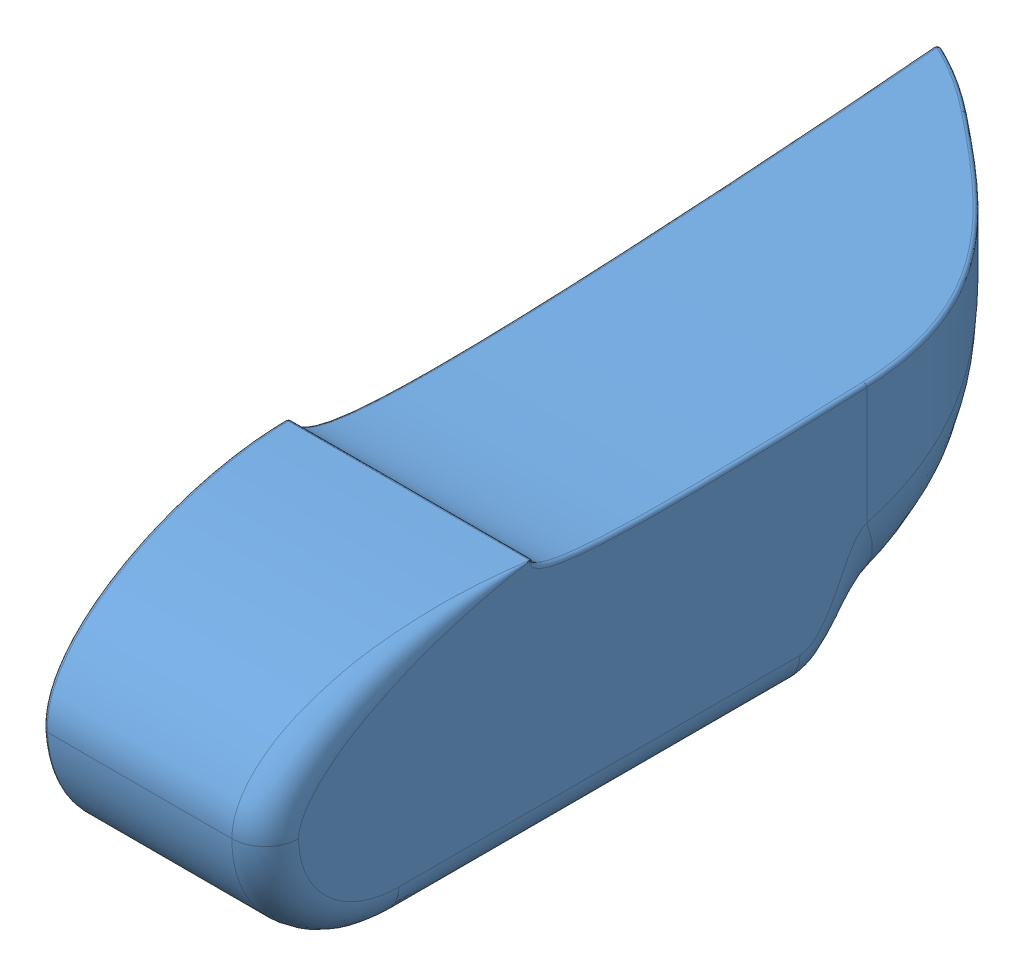
SolidWorks assembly Assem1, configuration Default. Lengths in mm.
Overall size (85.73 91.77 283.01).
2 component instances, 2 part files, 3 mates.
Components (placement in the parent):
- dropBox-1: dropBox [Default] at (93.9536 158.1472 83.8644) size (85.73 91.77 283.01)
- Latch Mirrored-1: Latch Mirrored [Default] at (111.7447 198.5141 164.3811) x (0 0 -1) z (1 0 0) size (38.1 29.84 38.1)
Mates (geometry in assembly coordinates):
- Coincident4: coincident aligned: plane of dropBox-1 through (93.5536 158.1472 203.8644) normal (0 0 1); plane of Latch Mirrored-1 through (106.4536 176.4347 203.8644) normal (0 0 1)
- Coincident5: coincident anti-aligned: plane of dropBox-1 through (144.5536 162.1472 203.8644) normal (0 1 0); plane of Latch Mirrored-1 through (144.5536 162.1472 184.8144) normal (0 -1 0)
- Coincident6: coincident aligned: plane of dropBox-1 through (144.5536 158.1472 83.8644) normal (1 0 0); plane of Latch Mirrored-1 through (144.5536 165.3222 184.8144) normal (1 0 0)
